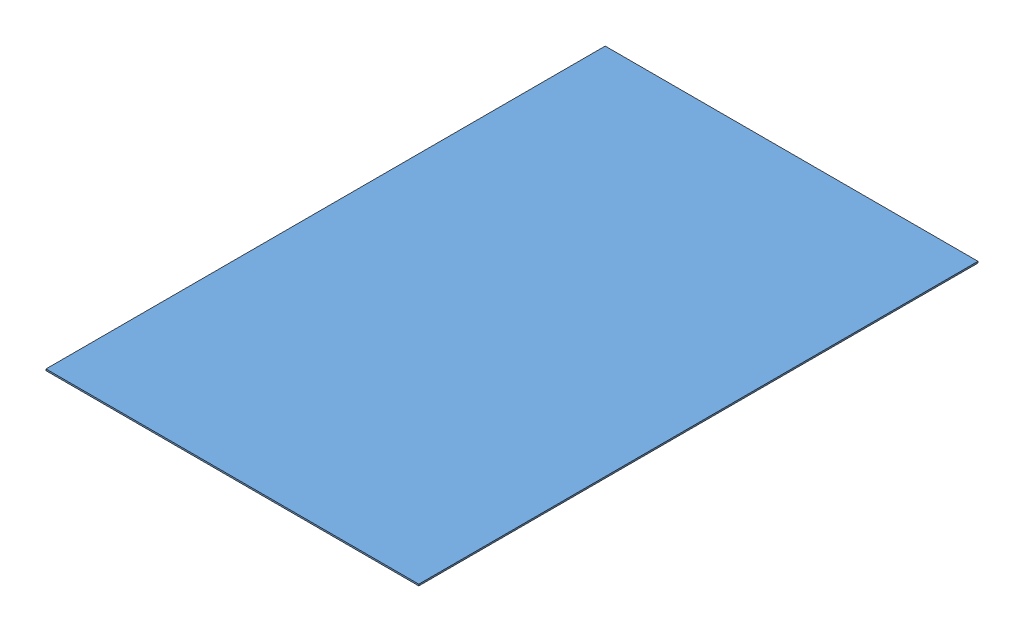
SolidWorks assembly Assem4, configuration Default. Lengths in mm.
Overall size (762 3.19 1143).
9 component instances, 3 part files, 24 mates.
Components (placement in the parent):
- alro bass aluminum sheat .25-48.5-144.5-1: alro bass aluminum sheat .25-48.5-144.5 [Default] at (1633.7678 1955.0883 2651.107) size (762 3.17 1143)
- OuterPlate_flat-1: OuterPlate_flat [DefaultSM-FLAT-PATTERN] at (1290.8678 1955.0883 3191.1034) size (711.2 3.17 116.35)
- OuterPlate_flat-2: OuterPlate_flat [DefaultSM-FLAT-PATTERN] at (1290.8678 1955.0883 3049.3562) size (711.2 3.17 116.35)
- OuterPlate_flat-3: OuterPlate_flat [DefaultSM-FLAT-PATTERN] at (1290.8678 1955.0883 2907.6091) size (711.2 3.17 116.35)
- OuterPlate_flat-4: OuterPlate_flat [DefaultSM-FLAT-PATTERN] at (1290.8678 1955.0883 2765.8619) size (711.2 3.17 116.35)
- InnerPlate_flat-1: InnerPlate_flat [Default] at (2002.0678 1955.0883 2542.1997) x (-1 0 0) z (0 0 -1) size (711.2 3.19 119.52)
- InnerPlate_flat-2: InnerPlate_flat [Default] at (2002.0678 1955.0883 2397.2775) x (-1 0 0) z (0 0 -1) size (711.2 3.19 119.52)
- InnerPlate_flat-3: InnerPlate_flat [Default] at (2002.0678 1955.0883 2252.3554) x (-1 0 0) z (0 0 -1) size (711.2 3.19 119.52)
- InnerPlate_flat-4: InnerPlate_flat [Default] at (2002.0678 1955.0883 2107.4332) x (-1 0 0) z (0 0 -1) size (711.2 3.19 119.52)
Mates (geometry in assembly coordinates):
- Coincident1: coincident aligned: plane of alro bass aluminum sheat .25-48.5-144.5-1 through (1633.7678 1958.2633 2651.107) normal (0 1 0); plane of OuterPlate_flat-1 through (1290.8678 1958.2633 3105.4164) normal (0 1 0)
- Coincident2: coincident aligned: plane of alro bass aluminum sheat .25-48.5-144.5-1 through (1633.7678 1958.2633 2651.107) normal (0 1 0); plane of OuterPlate_flat-2 through (1290.8678 1958.2633 2963.6692) normal (0 1 0)
- Coincident3: coincident aligned: plane of alro bass aluminum sheat .25-48.5-144.5-1 through (1633.7678 1958.2633 2651.107) normal (0 1 0); plane of OuterPlate_flat-3 through (1290.8678 1958.2633 2821.9221) normal (0 1 0)
- Coincident4: coincident aligned: plane of alro bass aluminum sheat .25-48.5-144.5-1 through (1633.7678 1958.2633 2651.107) normal (0 1 0); plane of OuterPlate_flat-4 through (1290.8678 1958.2633 2680.1749) normal (0 1 0)
- Coincident9: coincident aligned: line of OuterPlate_flat-1 through (2002.0678 1958.2633 3199.785) axis (0 0 -1); line of OuterPlate_flat-2 through (2002.0678 1958.2633 3058.0378) axis (0 0 -1)
- Coincident11: coincident: plane of OuterPlate_flat-2 through (2002.0678 1958.2633 3042.4092) normal (1 0 0); line of OuterPlate_flat-3 through (2002.0678 1958.2633 2916.2907) axis (0 0 -1)
- Coincident12: coincident aligned: line of OuterPlate_flat-3 through (2002.0678 1958.2633 2916.2907) axis (0 0 -1); line of OuterPlate_flat-4 through (2002.0678 1958.2633 2774.5435) axis (0 0 -1)
- Distance5: distance = 25.4 mm: line of OuterPlate_flat-2 through (1979.8428 1958.2633 3068.1598) axis (1 0 0); line of OuterPlate_flat-1 through (1796.3278 1958.2633 3093.5598) axis (-1 0 0)
- Distance6: distance = 25.4 mm: line of OuterPlate_flat-2 through (1998.8928 1958.2633 2951.8126) axis (-1 0 0); line of OuterPlate_flat-3 through (1979.8428 1958.2633 2926.4126) axis (1 0 0)
- Distance8: distance = 25.4 mm: line of OuterPlate_flat-3 through (1998.8928 1958.2633 2810.0655) axis (-1 0 0); line of OuterPlate_flat-4 through (1979.8428 1958.2633 2784.6655) axis (1 0 0)
- Coincident19: coincident aligned: plane of alro bass aluminum sheat .25-48.5-144.5-1 through (1633.7678 1958.2633 2651.107) normal (0 1 0); plane of InnerPlate_flat-1 through (2002.0678 1958.2633 2613.9927) normal (0 1 0)
- Distance13: distance = 25.4 mm: line of InnerPlate_flat-1 through (1290.8678 1958.2633 2642.9183) axis (1 0 0); line of OuterPlate_flat-4 through (1796.3278 1958.2633 2668.3183) axis (-1 0 0)
- Coincident25: coincident aligned: line of OuterPlate_flat-4 through (2002.0678 1958.2633 2774.5435) axis (0 0 -1); line of InnerPlate_flat-1 through (2002.0678 1958.2633 2635.9713) axis (0 0 -1)
- Coincident26: coincident aligned: plane of alro bass aluminum sheat .25-48.5-144.5-1 through (1633.7678 1958.2633 2651.107) normal (0 1 0); plane of InnerPlate_flat-2 through (2002.0678 1958.2633 2469.0706) normal (0 1 0)
- Coincident27: coincident aligned: plane of alro bass aluminum sheat .25-48.5-144.5-1 through (1633.7678 1958.2633 2651.107) normal (0 1 0); plane of InnerPlate_flat-3 through (2002.0678 1958.2633 2324.1484) normal (0 1 0)
- Coincident28: coincident aligned: plane of alro bass aluminum sheat .25-48.5-144.5-1 through (1633.7678 1958.2633 2651.107) normal (0 1 0); plane of InnerPlate_flat-4 through (2002.0678 1958.2633 2179.2262) normal (0 1 0)
- Distance15: distance = 25.4 mm: line of InnerPlate_flat-1 through (1290.8678 1958.2633 2523.3961) axis (1 0 0); line of InnerPlate_flat-2 through (1290.8678 1958.2633 2497.9961) axis (1 0 0)
- Coincident32: coincident aligned: line of InnerPlate_flat-1 through (2002.0678 1958.2633 2535.2527) axis (0 0 -1); line of InnerPlate_flat-2 through (2002.0678 1958.2633 2491.0491) axis (0 0 -1)
- Coincident33: coincident aligned: line of InnerPlate_flat-2 through (2002.0678 1958.2633 2491.0491) axis (0 0 -1); line of InnerPlate_flat-3 through (2002.0678 1958.2633 2346.127) axis (0 0 -1)
- Coincident34: coincident aligned: line of InnerPlate_flat-3 through (2002.0678 1958.2633 2346.127) axis (0 0 -1); line of InnerPlate_flat-4 through (2002.0678 1958.2633 2201.2048) axis (0 0 -1)
- Distance16: distance = 25.4 mm: line of InnerPlate_flat-3 through (1290.8678 1958.2633 2353.074) axis (1 0 0); line of InnerPlate_flat-2 through (1290.8678 1958.2633 2378.474) axis (1 0 0)
- Distance17: distance = 25.4 mm: line of InnerPlate_flat-3 through (1290.8678 1958.2633 2233.5518) axis (1 0 0); line of InnerPlate_flat-4 through (1290.8678 1958.2633 2208.1518) axis (1 0 0)
- Distance19: distance = 12.7 mm: line of OuterPlate_flat-1 through (2002.0678 1958.2633 3206.732) axis (0 0 -1); line of alro bass aluminum sheat .25-48.5-144.5-1 through (2014.7678 1958.2633 3222.607) axis (0 0 -1)
- Distance20: distance = 12.7 mm: line of OuterPlate_flat-1 through (1979.8428 1958.2633 3209.907) axis (1 0 0); line of alro bass aluminum sheat .25-48.5-144.5-1 through (1252.7678 1958.2633 3222.607) axis (1 0 0)
